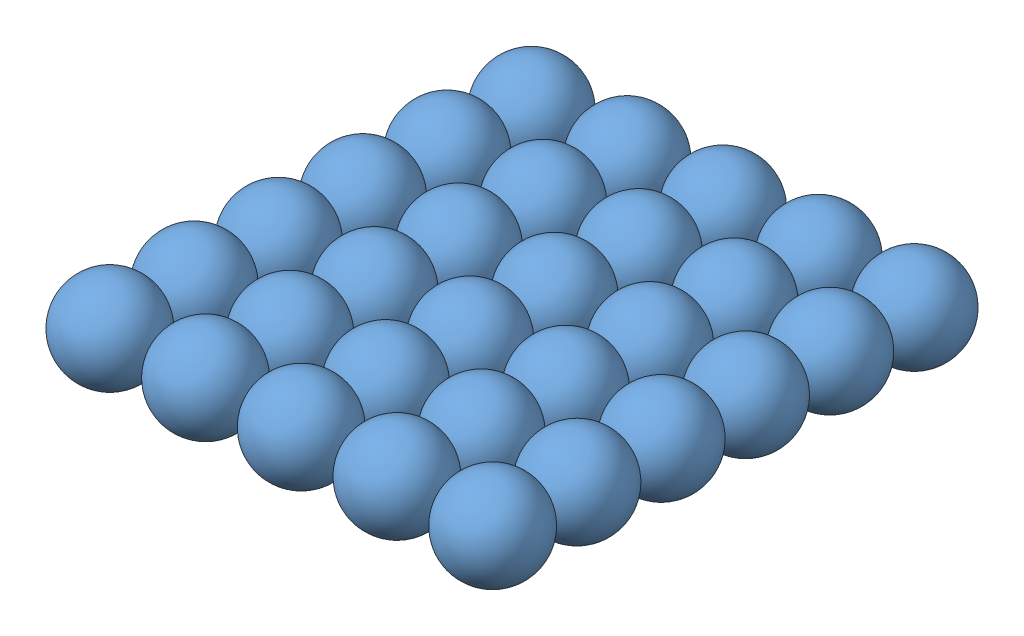
SolidWorks assembly GliderColonistsLayout_Balls, configuration Default. Lengths in mm.
Overall size (237.01 75.22 266.38).
31 component instances, 2 part files, 3 mates.
Components (placement in the parent):
- PingPongBall-1: PingPongBall [Default] at (103.3294 215.1982 85.0898) x (0.318433 -0.943803 -0.088524) z (0.332607 0.023792 0.942765) size (40.64 40.64 40.64)
- PingPongBall-146: PingPongBall [Default] at (100.888 210.8045 44.7619) x (0.318433 -0.943803 -0.088524) z (0.332607 0.023792 0.942765) size (40.64 40.64 40.64)
- PingPongBall-147: PingPongBall [Default] at (98.4466 206.4108 4.4339) x (0.318433 -0.943803 -0.088524) z (0.332607 0.023792 0.942765) size (40.64 40.64 40.64)
- PingPongBall-148: PingPongBall [Default] at (96.0052 202.017 -35.894) x (0.318433 -0.943803 -0.088524) z (0.332607 0.023792 0.942765) size (40.64 40.64 40.64)
- PingPongBall-149: PingPongBall [Default] at (93.5639 197.6233 -76.222) x (0.318433 -0.943803 -0.088524) z (0.332607 0.023792 0.942765) size (40.64 40.64 40.64)
- PingPongBall-150: PingPongBall [Default] at (91.1225 193.2296 -116.55) x (0.318433 -0.943803 -0.088524) z (0.332607 0.023792 0.942765) size (40.64 40.64 40.64)
- PingPongBall-151: PingPongBall [Default] at (62.763 215.3307 87.5312) x (0.318433 -0.943803 -0.088524) z (0.332607 0.023792 0.942765) size (40.64 40.64 40.64)
- PingPongBall-152: PingPongBall [Default] at (60.3216 210.937 47.2033) x (0.318433 -0.943803 -0.088524) z (0.332607 0.023792 0.942765) size (40.64 40.64 40.64)
- PingPongBall-153: PingPongBall [Default] at (57.8802 206.5432 6.8753) x (0.318433 -0.943803 -0.088524) z (0.332607 0.023792 0.942765) size (40.64 40.64 40.64)
- PingPongBall-154: PingPongBall [Default] at (55.4389 202.1495 -33.4527) x (0.318433 -0.943803 -0.088524) z (0.332607 0.023792 0.942765) size (40.64 40.64 40.64)
- PingPongBall-155: PingPongBall [Default] at (52.9975 197.7558 -73.7806) x (0.318433 -0.943803 -0.088524) z (0.332607 0.023792 0.942765) size (40.64 40.64 40.64)
- PingPongBall-156: PingPongBall [Default] at (50.5561 193.362 -114.1086) x (0.318433 -0.943803 -0.088524) z (0.332607 0.023792 0.942765) size (40.64 40.64 40.64)
- PingPongBall-157: PingPongBall [Default] at (22.1966 215.4632 89.9726) x (0.318433 -0.943803 -0.088524) z (0.332607 0.023792 0.942765) size (40.64 40.64 40.64)
- PingPongBall-158: PingPongBall [Default] at (19.7552 211.0694 49.6446) x (0.318433 -0.943803 -0.088524) z (0.332607 0.023792 0.942765) size (40.64 40.64 40.64)
- PingPongBall-159: PingPongBall [Default] at (17.3138 206.6757 9.3167) x (0.318433 -0.943803 -0.088524) z (0.332607 0.023792 0.942765) size (40.64 40.64 40.64)
- PingPongBall-160: PingPongBall [Default] at (14.8725 202.282 -31.0113) x (0.318433 -0.943803 -0.088524) z (0.332607 0.023792 0.942765) size (40.64 40.64 40.64)
- PingPongBall-161: PingPongBall [Default] at (12.4311 197.8883 -71.3393) x (0.318433 -0.943803 -0.088524) z (0.332607 0.023792 0.942765) size (40.64 40.64 40.64)
- PingPongBall-162: PingPongBall [Default] at (9.9897 193.4945 -111.6672) x (0.318433 -0.943803 -0.088524) z (0.332607 0.023792 0.942765) size (40.64 40.64 40.64)
- DroneFrame_Ver_2-1: DroneFrame_Ver_2 [Default] at (16.1646 182.6999 -8.4788) x (0.998189 -0.00326 -0.060073) z (0.060073 0.108113 0.992322) size (206.38 45.4 277.68) (hidden)
- PingPongBall-187: PingPongBall [Default] at (-18.3698 215.5957 92.414) x (0.318433 -0.943803 -0.088524) z (0.332607 0.023792 0.942765) size (40.64 40.64 40.64)
- PingPongBall-188: PingPongBall [Default] at (-20.8112 211.2019 52.086) x (0.318433 -0.943803 -0.088524) z (0.332607 0.023792 0.942765) size (40.64 40.64 40.64)
- PingPongBall-189: PingPongBall [Default] at (-23.2525 206.8082 11.758) x (0.318433 -0.943803 -0.088524) z (0.332607 0.023792 0.942765) size (40.64 40.64 40.64)
- PingPongBall-190: PingPongBall [Default] at (-25.6939 202.4145 -28.5699) x (0.318433 -0.943803 -0.088524) z (0.332607 0.023792 0.942765) size (40.64 40.64 40.64)
- PingPongBall-191: PingPongBall [Default] at (-28.1353 198.0207 -68.8979) x (0.318433 -0.943803 -0.088524) z (0.332607 0.023792 0.942765) size (40.64 40.64 40.64)
- PingPongBall-192: PingPongBall [Default] at (-30.5767 193.627 -109.2258) x (0.318433 -0.943803 -0.088524) z (0.332607 0.023792 0.942765) size (40.64 40.64 40.64)
- PingPongBall-193: PingPongBall [Default] at (-58.9362 215.7281 94.8553) x (0.318433 -0.943803 -0.088524) z (0.332607 0.023792 0.942765) size (40.64 40.64 40.64)
- PingPongBall-194: PingPongBall [Default] at (-61.3775 211.3344 54.5274) x (0.318433 -0.943803 -0.088524) z (0.332607 0.023792 0.942765) size (40.64 40.64 40.64)
- PingPongBall-195: PingPongBall [Default] at (-63.8189 206.9407 14.1994) x (0.318433 -0.943803 -0.088524) z (0.332607 0.023792 0.942765) size (40.64 40.64 40.64)
- PingPongBall-196: PingPongBall [Default] at (-66.2603 202.5469 -26.1285) x (0.318433 -0.943803 -0.088524) z (0.332607 0.023792 0.942765) size (40.64 40.64 40.64)
- PingPongBall-197: PingPongBall [Default] at (-68.7017 198.1532 -66.4565) x (0.318433 -0.943803 -0.088524) z (0.332607 0.023792 0.942765) size (40.64 40.64 40.64)
- PingPongBall-198: PingPongBall [Default] at (-71.1431 193.7595 -106.7845) x (0.318433 -0.943803 -0.088524) z (0.332607 0.023792 0.942765) size (40.64 40.64 40.64)
Mates (geometry in assembly coordinates):
- Tangent6: tangent anti-aligned: sphere of PingPongBall-150; plane of DroneFrame_Ver_2-1 through (8.8353 171.0969 -129.6343) normal (0.060073 0.108113 0.992322)
- Tangent7: tangent anti-aligned: sphere of PingPongBall-150; plane of DroneFrame_Ver_2-1 through (117.5754 183.9469 -14.7539) normal (-0.998189 0.00326 0.060073)
- Tangent8: tangent anti-aligned: sphere of PingPongBall-150; plane of DroneFrame_Ver_2-1 through (16.1594 184.2781 -8.6504) normal (-0.00326 0.994133 -0.108113)
